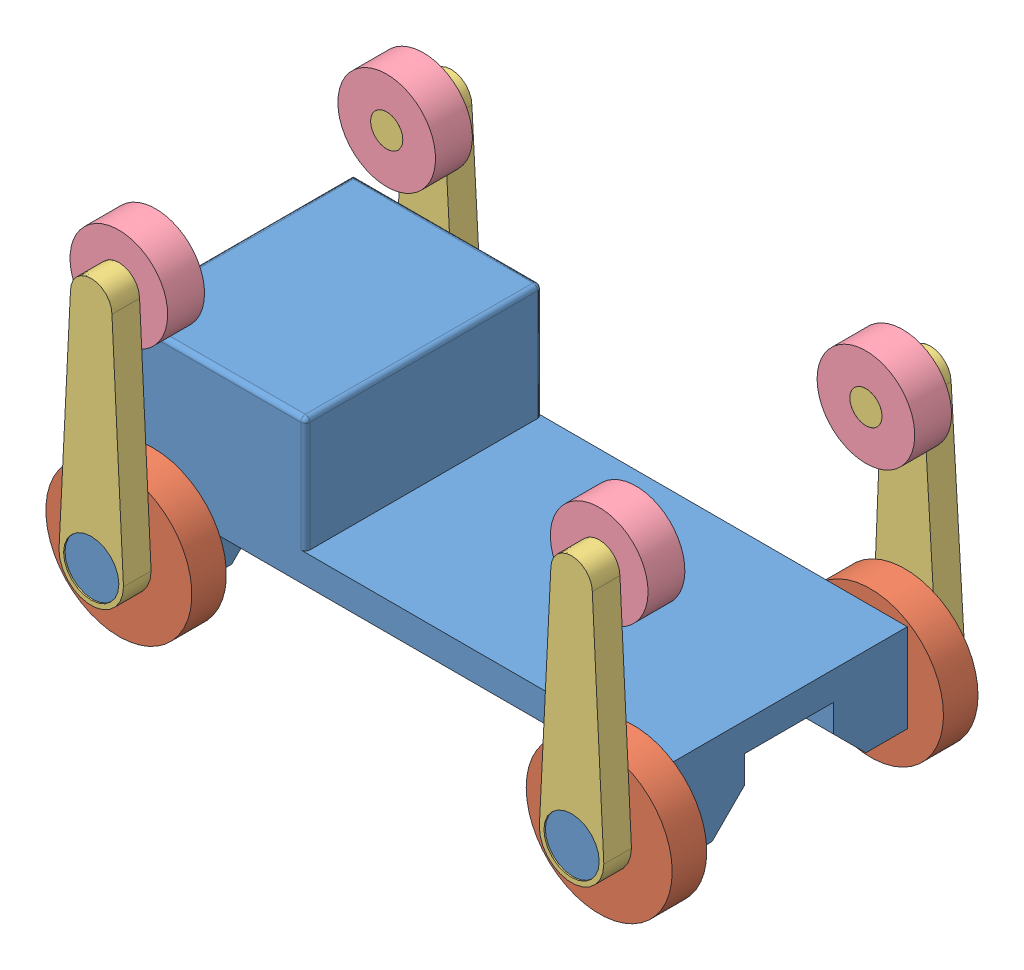
SolidWorks assembly PrimeChair, configuration По умолчанию. Lengths in mm.
Overall size (1457.25 845.64 784).
13 component instances, 4 part files, 24 mates.
Components (placement in the parent):
- base-1: base [По умолчанию] at (1.2011 -2.4191 1203) size (1203 442 778)
- BigWheel-1: BigWheel [По умолчанию] at (-520.2989 -67.4191 1460) x (0.275541 -0.961289 0) z (0 0 1) size (317 317 75)
- BigWheel-2: BigWheel [По умолчанию] at (-520.2989 -67.4191 946) x (-0.923728 -0.383049 0) z (0 0 -1) size (317 317 75)
- BigWheel-3: BigWheel [По умолчанию] at (522.7011 -67.4191 1460) size (317 317 75)
- BigWheel-4: BigWheel [По умолчанию] at (522.7011 -67.4191 946) x (-0.923728 -0.383049 0) z (0 0 -1) size (317 317 75)
- Noga-1: Noga [По умолчанию] at (-520.2989 -67.4191 1535) size (140 615 140)
- Noga-2: Noga [По умолчанию] at (522.7011 -67.4191 1535) size (140 615 140)
- Noga-3: Noga [По умолчанию] at (-520.2989 -67.4191 871) x (-0.999988 -0.004874 0) z (0 0 -1) size (140 615 140)
- Noga-4: Noga [По умолчанию] at (522.7011 -67.4191 871) x (-0.999952 -0.009752 0) z (0 0 -1) size (140 615 140)
- SmallWheel-1: SmallWheel [По умолчанию] at (-522.736 432.5749 871) size (212 212 80)
- SmallWheel-2: SmallWheel [По умолчанию] at (517.8252 432.5571 871) size (212 212 80)
- SmallWheel-3: SmallWheel [По умолчанию] at (522.7011 432.5809 1535) x (-0.923728 -0.383049 0) z (0 0 -1) size (212 212 80)
- SmallWheel-4: SmallWheel [По умолчанию] at (-520.2989 432.5809 1535) x (-0.923728 -0.383049 0) z (0 0 -1) size (212 212 80)
Mates (geometry in assembly coordinates):
- Концентричный1: concentric aligned: cylinder of base-1 through (-520.2989 -67.4191 1592) axis (0 0 -1) radius 60; cylinder of BigWheel-1 through (-520.2989 -67.4191 1535) axis (0 0 -1) radius 60
- Совпадение1: coincident anti-aligned: plane of base-1 through (-600.2989 59.5809 1460) normal (0 0 1); plane of BigWheel-1 through (-520.2989 -67.4191 1460) normal (0 0 -1)
- Совпадение2: coincident anti-aligned: plane of base-1 through (-600.2989 59.5809 946) normal (0 0 -1); plane of BigWheel-2 through (-520.2989 -67.4191 946) normal (0 0 1)
- Концентричный2: concentric aligned: cylinder of base-1 through (-520.2989 -67.4191 814) axis (0 0 1) radius 60; cylinder of BigWheel-2 through (-520.2989 -67.4191 871) axis (0 0 1) radius 60
- Совпадение3: coincident anti-aligned: plane of base-1 through (-600.2989 59.5809 1460) normal (0 0 1); plane of BigWheel-3 through (522.7011 -67.4191 1460) normal (0 0 -1)
- Концентричный3: concentric aligned: cylinder of base-1 through (522.7011 -67.4191 1592) axis (0 0 -1) radius 60; cylinder of BigWheel-3 through (522.7011 -67.4191 1535) axis (0 0 -1) radius 60
- Совпадение4: coincident anti-aligned: plane of base-1 through (-600.2989 59.5809 946) normal (0 0 -1); plane of BigWheel-4 through (522.7011 -67.4191 946) normal (0 0 1)
- Концентричный4: concentric aligned: cylinder of base-1 through (522.7011 -67.4191 814) axis (0 0 1) radius 60; cylinder of BigWheel-4 through (522.7011 -67.4191 871) axis (0 0 1) radius 60
- Концентричный5: concentric anti-aligned: cylinder of base-1 through (-520.2989 -67.4191 1592) axis (0 0 -1) radius 60; cylinder of Noga-1 through (-520.2989 -67.4191 1535) axis (0 0 1) radius 60
- Совпадение5: coincident anti-aligned: plane of BigWheel-1 through (-520.2989 -67.4191 1535) normal (0 0 1); plane of Noga-1 through (-520.2989 -67.4191 1535) normal (0 0 -1)
- Концентричный6: concentric anti-aligned: cylinder of base-1 through (522.7011 -67.4191 1592) axis (0 0 -1) radius 60; cylinder of Noga-2 through (522.7011 -67.4191 1535) axis (0 0 1) radius 60
- Совпадение6: coincident anti-aligned: plane of BigWheel-3 through (522.7011 -67.4191 1535) normal (0 0 1); plane of Noga-2 through (522.7011 -67.4191 1535) normal (0 0 -1)
- Концентричный7: concentric anti-aligned: cylinder of base-1 through (-520.2989 -67.4191 814) axis (0 0 1) radius 60; cylinder of Noga-3 through (-520.2989 -67.4191 871) axis (0 0 -1) radius 60
- Совпадение8: coincident anti-aligned: plane of BigWheel-2 through (-520.2989 -67.4191 871) normal (0 0 -1); plane of Noga-3 through (-520.2989 -67.4191 871) normal (0 0 1)
- Концентричный8: concentric anti-aligned: cylinder of base-1 through (522.7011 -67.4191 814) axis (0 0 1) radius 60; cylinder of Noga-4 through (522.7011 -67.4191 871) axis (0 0 -1) radius 60
- Совпадение9: coincident anti-aligned: plane of BigWheel-4 through (522.7011 -67.4191 871) normal (0 0 -1); plane of Noga-4
- Концентричный10: concentric aligned: cylinder of Noga-3 through (-522.736 432.5749 951) axis (0 0 -1) radius 35; cylinder of SmallWheel-1 through (-522.736 432.5749 951) axis (0 0 -1) radius 35
- Совпадение10: coincident aligned: plane of Noga-3 through (-522.736 432.5749 951) normal (0 0 1); plane of SmallWheel-1 through (-522.736 432.5749 951) normal (0 0 1)
- Концентричный11: concentric aligned: cylinder of Noga-4 through (517.8252 432.5571 951) axis (0 0 -1) radius 35; cylinder of SmallWheel-2 through (517.8252 432.5571 951) axis (0 0 -1) radius 35
- Совпадение11: coincident anti-aligned: plane of Noga-4 through (522.7011 -67.4191 871) normal (0 0 1); plane of SmallWheel-2 through (517.8252 432.5571 871) normal (0 0 -1)
- Концентричный12: concentric aligned: cylinder of Noga-2 through (522.7011 432.5809 1455) axis (0 0 1) radius 35; cylinder of SmallWheel-3 through (522.7011 432.5809 1455) axis (0 0 1) radius 35
- Совпадение12: coincident aligned: plane of Noga-2 through (522.7011 432.5809 1455) normal (0 0 -1); plane of SmallWheel-3 through (522.7011 432.5809 1455) normal (0 0 -1)
- Концентричный13: concentric aligned: cylinder of Noga-1 through (-520.2989 432.5809 1455) axis (0 0 1) radius 35; cylinder of SmallWheel-4 through (-520.2989 432.5809 1455) axis (0 0 1) radius 35
- Совпадение13: coincident aligned: plane of Noga-1 through (-520.2989 432.5809 1455) normal (0 0 -1); plane of SmallWheel-4 through (-520.2989 432.5809 1455) normal (0 0 -1)
